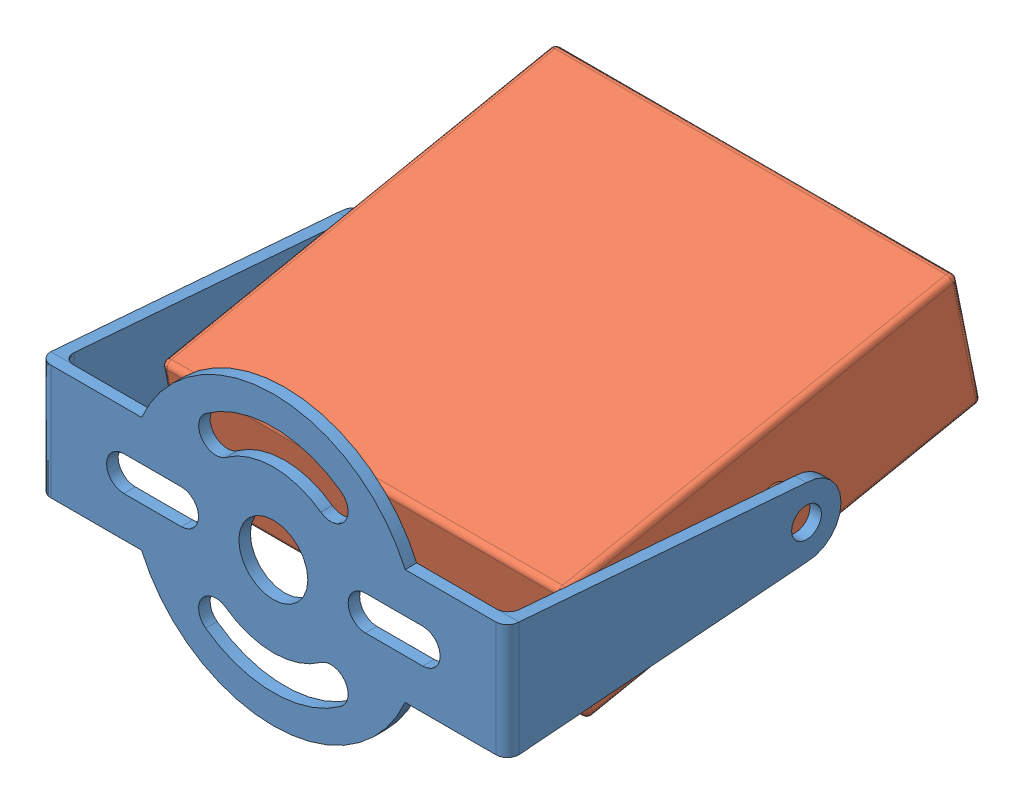
SolidWorks assembly Cam_ass, configuration 默认. Lengths in mm.
2 component instances, 2 part files, 2 mates.
Components (placement in the parent):
- Cam_base-1: Cam_base [默认] at (0.5231 -0.8283 54.2) size (40.7 25 29)
- Cam_main-1: Cam_main [Default] at (0.5231 5.0528 30.3888) x (0 -0.198131 0.980176) z (0 -0.980176 -0.198131) size (1072 1072 2022.5)
Mates (geometry in assembly coordinates):
- Concentric1: concentric: cylinder of Cam_base-1 through (-18.8269 -0.8283 29.2) axis (-1 0 0) radius 1.3; cylinder of Cam_main-1 through (13.0231 -0.8283 29.2) axis (1 0 0) radius 1.5
- Distance1: distance = 1.85 mm: plane of Cam_base-1 through (-18.8269 -0.8283 54.2) normal (1 0 0); plane of Cam_main-1 through (-16.9769 -2.2619 11.0563) normal (-1 0 0)
